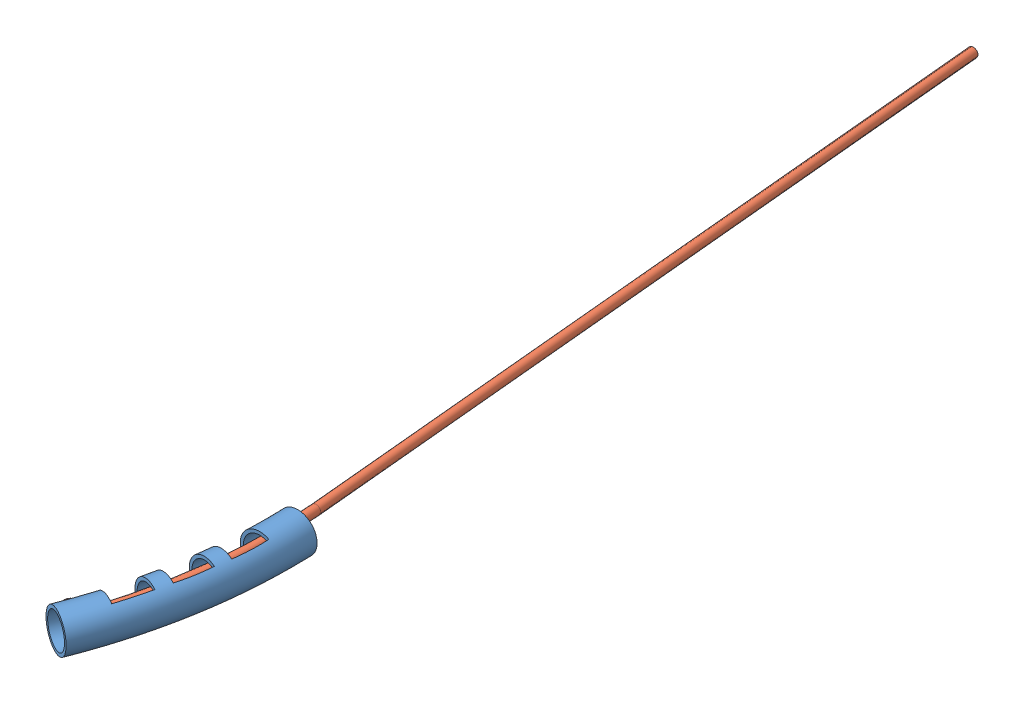
SolidWorks assembly cable + square joint_curve 1 assem, configuration Default. Lengths in mm.
Overall size (22.47 1.31 31.85).
2 component instances, 2 part files, 1 mates.
Components (placement in the parent):
- Arushri_Tube_SquareJoint_curve 1-1: Arushri_Tube_SquareJoint_curve 1 [Default] at (4.2781 6.1391 7.6247) size (2.5 1.31 18)
- cable_curve1-1: cable_curve1 [Default] at (2.7697 6.1391 13.4282) x (0.92362 0 0.383309) z (0 -1 0) size (12.89 27.55 0.5)
Mates (geometry in assembly coordinates):
- Coincident1: coincident anti-aligned: circle of Arushri_Tube_SquareJoint_curve 1-1; circle of cable_curve1-1
